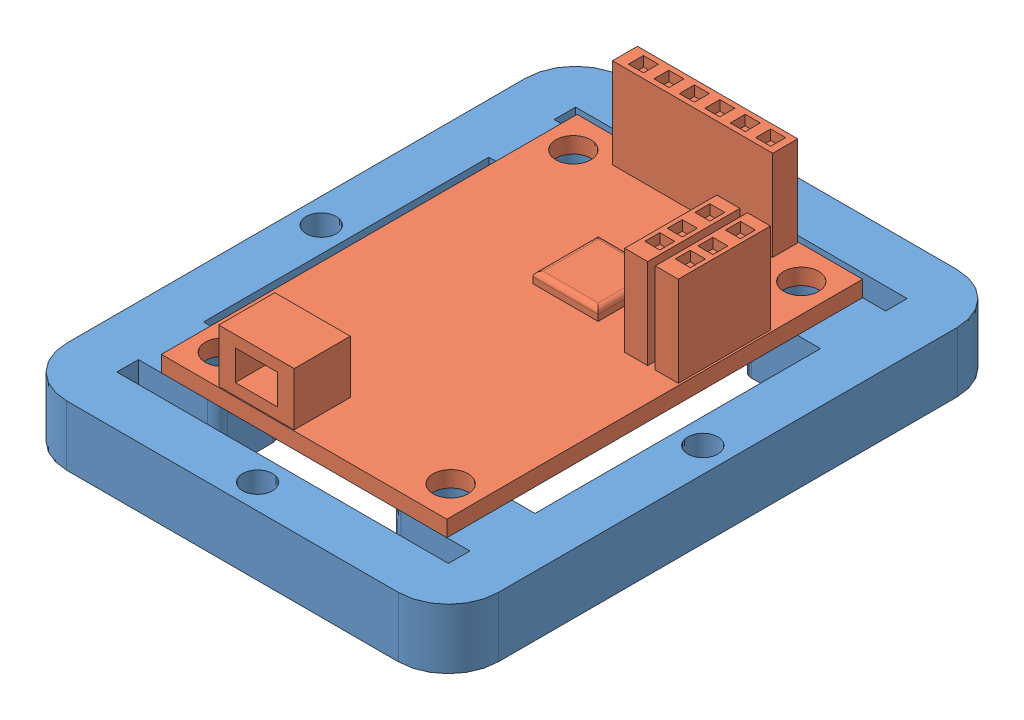
SolidWorks assembly Assem1, configuration Default. Lengths in mm.
Overall size (43.1 16.6 55.8).
2 component instances, 2 part files, 3 mates.
Components (placement in the parent):
- razor_imu_mount-1: razor_imu_mount [Default] at (-9.4532 -1.4366 5.9643) size (43.1 6 55.8)
- razor_imu-1: razor_imu [Default] at (-9.4532 4.5634 5.9643) size (28.5 10.6 41.5)
Mates (geometry in assembly coordinates):
- Concentric1: concentric: cylinder of razor_imu_mount-1 through (-20.8282 4.5634 23.4643) axis (0 -1 0) radius 1.75; cylinder of razor_imu-1 through (-20.8282 9.0298 23.4643) axis (0 -1 0) radius 1.75
- Concentric2: concentric: cylinder of razor_imu_mount-1 through (1.9218 4.5634 23.4643) axis (0 -1 0) radius 1.75; cylinder of razor_imu-1 through (1.9218 9.0298 23.4643) axis (0 -1 0) radius 1.75
- Coincident2: coincident anti-aligned: plane of razor_imu_mount-1 through (-31.0032 4.5634 33.8643) normal (0 1 0); plane of razor_imu-1 through (4.7968 4.5634 -14.7857) normal (0 -1 0)
